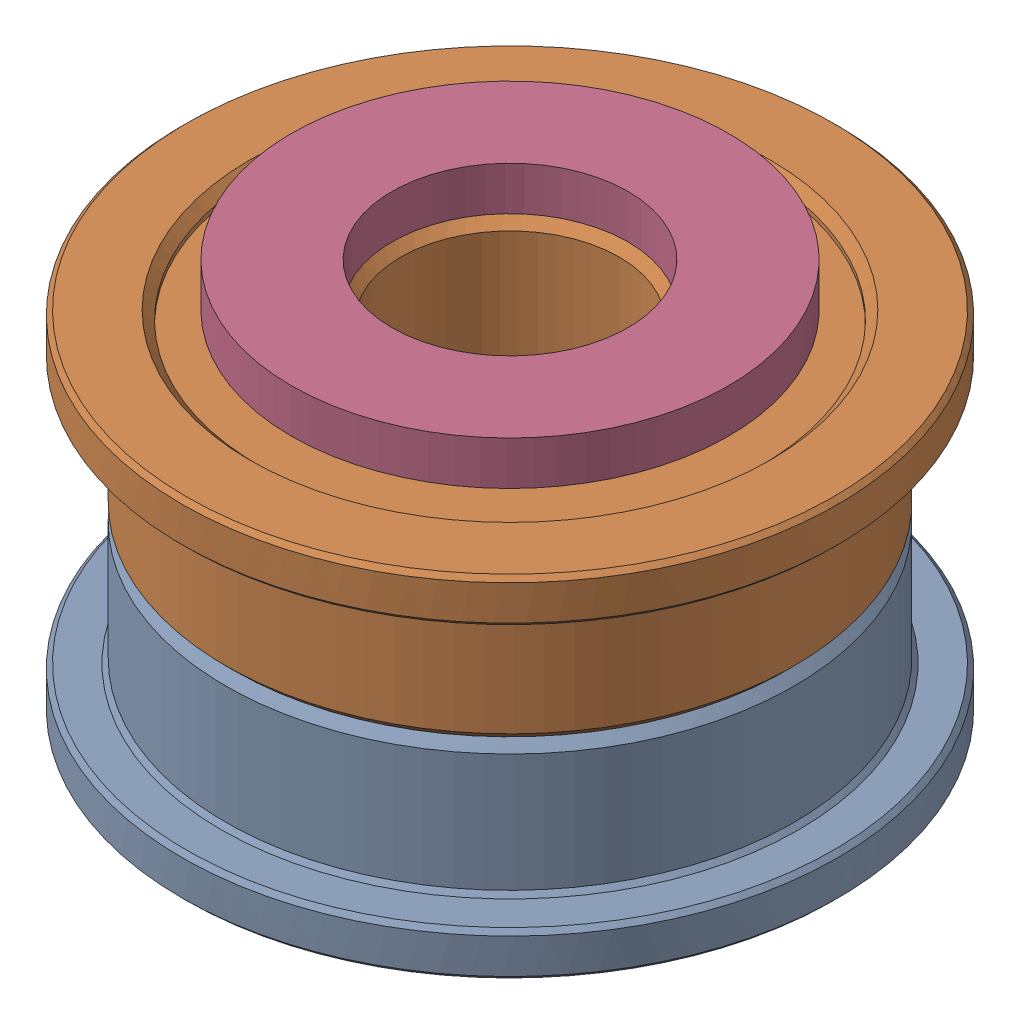
SolidWorks assembly Idler Pulley Assembly v3 (1), configuration Default. Lengths in mm.
Overall size (15 10 15).
4 component instances, 3 part files, 0 mates.
Components (placement in the parent):
- F695-2RS v1 (1) (1)-1: F695-2RS v1 (1) (1) [Default] at origin size (15 4 15)
- F695-2RS v1 (2) (1)-1: F695-2RS v1 (2) (1) [Default] at (0 8 0) x (-1 0 0) z (0 0 1) size (15 4 15)
- M5 1mm Spacer (2)-1: M5 1mm Spacer (2) [Default] at (0 0 350) size (10 1 10)
- M5 1mm Spacer (2)-2: M5 1mm Spacer (2) [Default] at (0 9 350) size (10 1 10)
